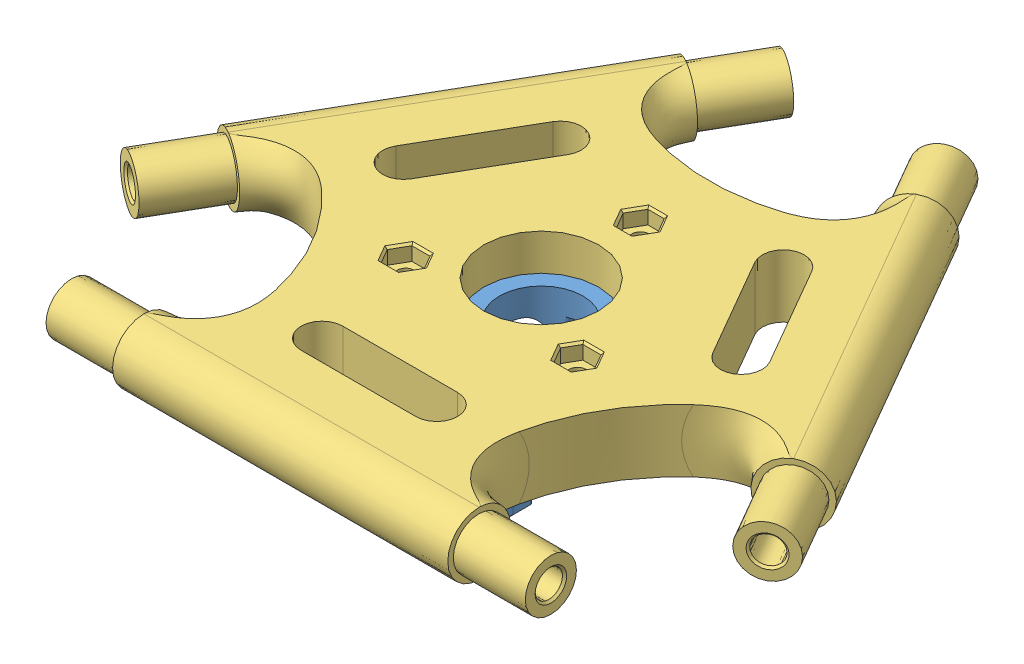
SolidWorks assembly pen-holder, configuration Default. Lengths in mm.
Overall size (130.67 41.58 114.22).
4 component instances, 3 part files, 8 mates.
Components (placement in the parent):
- pen-holder-duct-1: pen-holder-duct [Default] at origin size (44.21 25 40.52)
- pen-holder-1: pen-holder [Default] at (0.2 0 0.1653) x (0 0 1) z (0 -1 0) size (20.4 9 20)
- pen-holder-2: pen-holder [Default] at (-0.2 0 0.1653) x (0 0 -1) z (0 -1 0) size (20.4 9 20)
- flange-star-1: flange-star [Default] at (0 12 0) x (-1 0 0) z (0 0 1) size (130.67 31.15 114.22)
Mates (geometry in assembly coordinates):
- Coincident1: coincident: plane of pen-holder-1 through (0.2 -20 0.1653) normal (0 -1 0); plane of pen-holder-2 through (-0.2 -20 0.1653) normal (0 -1 0)
- Coincident2: coincident: plane of pen-holder-1 through (0.2 -20 10.3653) normal (0 0 1); plane of pen-holder-2 through (-0.2 -20 10.3653) normal (0 0 1)
- Coincident3: coincident: plane of pen-holder-1 through (0 0 0.1653) normal (1 0 0); plane of pen-holder-2 through (0 0 0.1653) normal (-1 0 0)
- Distance1: distance = 0.7 mm: plane of pen-holder-1 through (-1.8 -20 -5.3854) normal (-1 0 0); plane of pen-holder-duct-1 through (-2.5 -20 -10.3347) normal (1 0 0)
- Distance2: distance = 0.7 mm: plane of pen-holder-duct-1 through (2.1 -20 -10.7347) normal (0 0 1); plane of pen-holder-1 through (0.2 -20 -10.0347) normal (0 0 -1)
- Coincident7: coincident: plane of pen-holder-duct-1 through (5.3007 0 -8.9914) normal (0 -1 0); plane of pen-holder-1 through (0.2 0 0.1653) normal (0 1 0)
- Coincident8: coincident: plane of pen-holder-duct-1 through (5.3007 5 -8.9914) normal (0 1 0); plane of flange-star-1 through (5.419 5 -18.5519) normal (0 -1 0)
- Concentric1: concentric: cylinder of pen-holder-duct-1 through (-16.4545 5 9.5) axis (0 -1 0) radius 1.65; cylinder of flange-star-1 through (-16.4545 -9.5681 9.5) axis (0 1 0) radius 1.625
